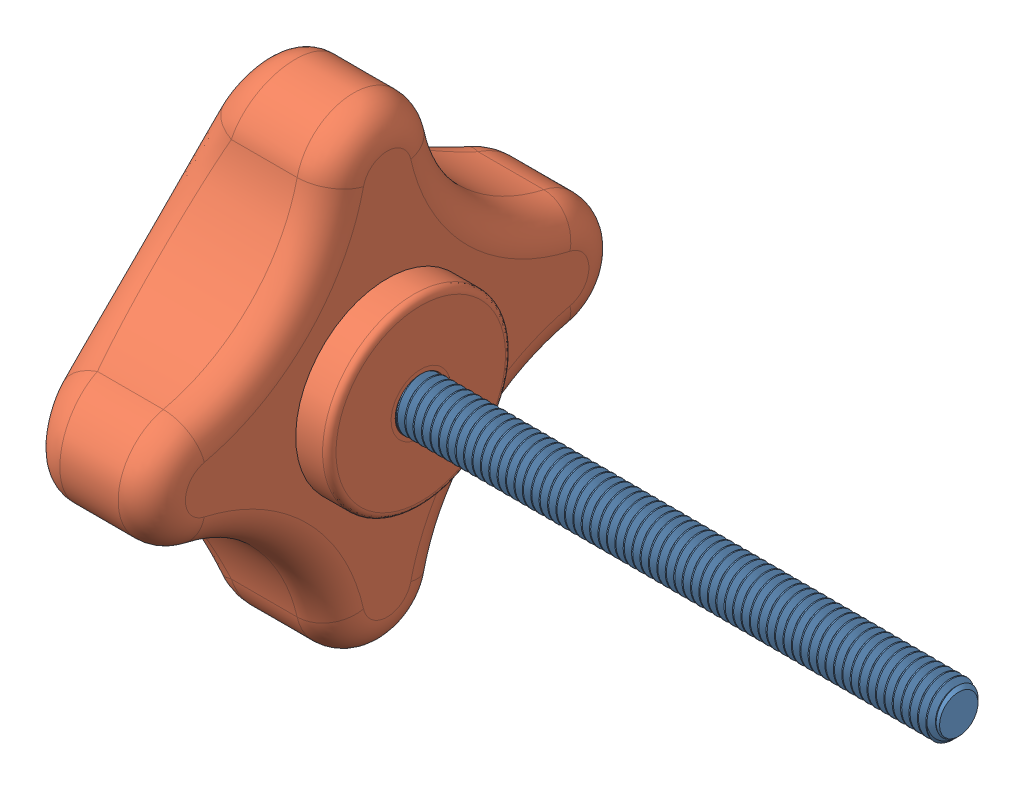
SolidWorks assembly Mold_Clamp_revB, configuration Default. Lengths in mm.
Overall size (70.57 44.45 44.45).
2 component instances, 2 part files, 2 mates.
Components (placement in the parent):
- 10-32_rod-1: 10-32_rod [95412A897] at (22.5349 40.3264 46.0491) size (64.69 4.89 5.57)
- threaded_four_arm_knob-1: threaded_four_arm_knob [2454K23] at (-2.8651 40.3264 46.0491) x (0 0 1) z (-1 0 0) size (44.45 44.45 19.36)
Mates (geometry in assembly coordinates):
- Concentric1: concentric anti-aligned: circle of 10-32_rod-1; circle of threaded_four_arm_knob-1
- Coincident2: coincident anti-aligned: plane of 10-32_rod-1 through (-9.2151 40.3264 46.0491) normal (-1 0 0); plane of threaded_four_arm_knob-1 through (-9.2151 40.3264 46.0491) normal (1 0 0)
